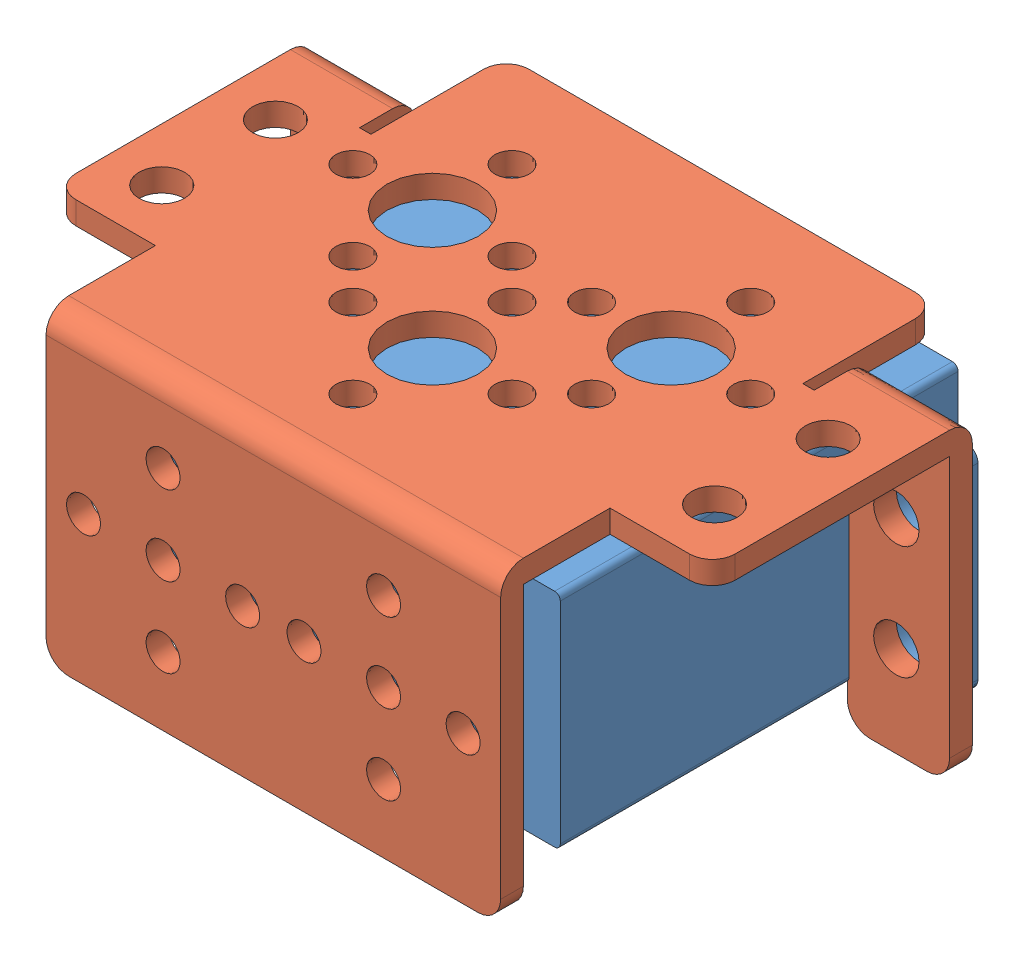
SolidWorks assembly 舵机与支架装配图（反装）, configuration 默认. Lengths in mm.
Overall size (58 27 48.1).
2 component instances, 2 part files, 4 mates.
Components (placement in the parent):
- MG995舵机-2: MG995舵机 [默认] at (-1.9429 16.1092 -14.4333) size (54 19.5 43)
- 舵机支架-2: 舵机支架 [默认] at (9.5712 21.0726 4.9167) x (-1 0 0) z (0 -1 0) size (58 39.5 27)
Mates (geometry in assembly coordinates):
- 同心6: concentric anti-aligned: circle of MG995舵机-2; circle of 舵机支架-2
- 同心7: concentric anti-aligned: circle of MG995舵机-2; circle of 舵机支架-2
- 重合1: coincident anti-aligned: plane of MG995舵机-2 through (36.5712 -2.1774 -6.8333) normal (0 0 1); plane of 舵机支架-2 through (36.5712 -3.9274 -6.8333) normal (0 0 -1)
- 同心8: concentric anti-aligned: circle of MG995舵机-2; circle of 舵机支架-2
